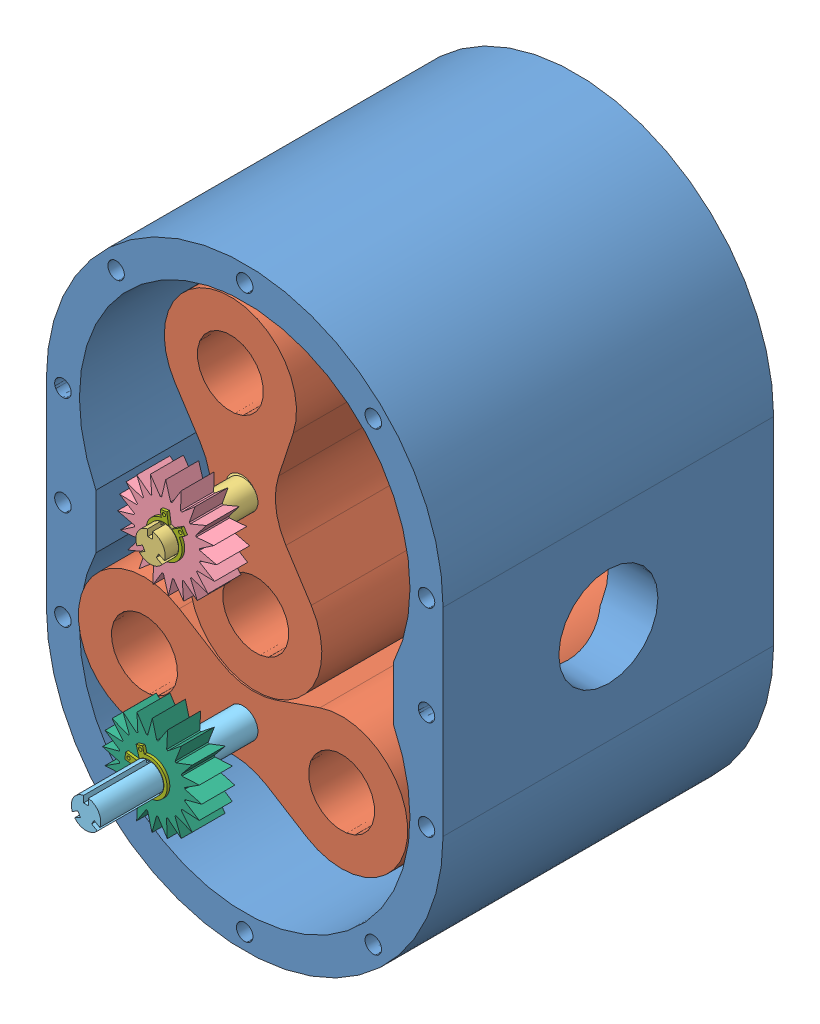
SolidWorks assembly 01-21-A-000-R00 Lobe Compressor Assembly, configuration Default. Lengths in mm.
Overall size (120 180 148).
9 component instances, 7 part files, 20 mates.
Components (placement in the parent):
- 01-21-P-001-R00 Compressor Housing-1: 01-21-P-001-R00 Compressor Housing [Default] at origin size (120 180 100)
- 01-21-P-002-R00 Compressor Top Lobe-1: 01-21-P-002-R00 Compressor Top Lobe [Default] at (0 30 5.5) x (0.991825 0.127605 0) z (0 0 1) size (40 100 90)
- 01-21-P-002-R00 Compressor Top Lobe-2: 01-21-P-002-R00 Compressor Top Lobe [Default] at (0 -30 5.5) x (-0.110138 -0.993916 0) z (0 0 1) size (40 100 90)
- 01-21-P-004-R00 Driven Lobe Shaft-1: 01-21-P-004-R00 Driven Lobe Shaft [Default] at (0 30 -46.5) x (0.999532 0.030602 0) z (0 0 1) size (10.29 11.89 125)
- 01-21-P-005-R00 Driven Lobe Shaft Gear-1: 01-21-P-005-R00 Driven Lobe Shaft Gear [Default] at (0 30 63.5) x (0.99962 0.027579 0) z (0 0 1) size (30 30 10)
- 01-21-P-006-R00 Drive Lobe Shaft-1: 01-21-P-006-R00 Drive Lobe Shaft [Default] at (0 -30 -47) x (0.999995 -0.003242 0) z (0 0 1) size (10.29 11.89 145)
- 01-21-P-007-R00 Drive Lobe Shaft Gear-1: 01-21-P-007-R00 Drive Lobe Shaft Gear [Default] at (0 -30 68) x (0.999995 -0.003242 0) z (0 0 1) size (30 30 10)
- 01-21-P-008-Lobe Shaft Retaining Ring-3: 01-21-P-008-Lobe Shaft Retaining Ring [Default] at (0 -30 78.1) x (0.657768 0.75322 0) z (0 0 1) size (10.9 12.78 0.8)
- 01-21-P-008-Lobe Shaft Retaining Ring-4: 01-21-P-008-Lobe Shaft Retaining Ring [Default] at (0 30 73.6) x (0.910939 -0.412541 0) z (0 0 1) size (10.9 12.78 0.8)
Mates (geometry in assembly coordinates):
- Coincident1: coincident aligned: plane of 01-21-P-001-R00 Compressor Housing-1 through (0 0 0) normal (0 1 0); plane of assembly through (0 0 0) normal (0 1 0)
- Coincident2: coincident aligned: plane of 01-21-P-001-R00 Compressor Housing-1 through (0 0 0) normal (0 0 1); plane of assembly through (0 0 0) normal (0 0 1)
- Coincident3: coincident aligned: plane of 01-21-P-001-R00 Compressor Housing-1 through (0 0 0) normal (1 0 0); plane of assembly through (0 0 0) normal (1 0 0)
- Concentric1: concentric aligned: circle of 01-21-P-001-R00 Compressor Housing-1; circle of 01-21-P-002-R00 Compressor Top Lobe-1
- Distance1: distance = 0.5 mm anti-aligned: plane of 01-21-P-002-R00 Compressor Top Lobe-1 through (-3.8282 59.7548 -39.5) normal (0 0 -1); plane of 01-21-P-001-R00 Compressor Housing-1 through (0 30 -40) normal (0 0 1)
- Concentric2: concentric aligned: circle of 01-21-P-001-R00 Compressor Housing-1; circle of 01-21-P-002-R00 Compressor Top Lobe-2
- Distance2: distance = 0.5 mm anti-aligned: plane of 01-21-P-002-R00 Compressor Top Lobe-2 through (29.8175 -33.3041 -39.5) normal (0 0 -1); plane of 01-21-P-001-R00 Compressor Housing-1 through (0 30 -40) normal (0 0 1)
- Concentric3: concentric aligned: circle of 01-21-P-002-R00 Compressor Top Lobe-1; circle of 01-21-P-004-R00 Driven Lobe Shaft-1
- Distance4: distance = 0.5 mm anti-aligned: plane of 01-21-P-004-R00 Driven Lobe Shaft-1 through (0 30 -46.5) normal (0 0 -1); plane of 01-21-P-001-R00 Compressor Housing-1 through (0 30 -47) normal (0 0 1)
- Concentric4: concentric aligned: circle of 01-21-P-004-R00 Driven Lobe Shaft-1; circle of 01-21-P-005-R00 Driven Lobe Shaft Gear-1
- Coincident6: coincident anti-aligned: plane of 01-21-P-004-R00 Driven Lobe Shaft-1 through (0 30 63.5) normal (0 0 1); plane of 01-21-P-005-R00 Driven Lobe Shaft Gear-1 through (0 30 63.5) normal (0 0 -1)
- Concentric5: concentric aligned: circle of 01-21-P-002-R00 Compressor Top Lobe-2; circle of 01-21-P-006-R00 Drive Lobe Shaft-1
- Coincident7: coincident anti-aligned: plane of 01-21-P-001-R00 Compressor Housing-1 through (0 -30 -47) normal (0 0 1); plane of 01-21-P-006-R00 Drive Lobe Shaft-1 through (0 -30 -47) normal (0 0 -1)
- Width1: width anti-aligned: plane of 01-21-P-006-R00 Drive Lobe Shaft-1 through (0.7578 -27.5953 68) normal (-0.999995 0.003242 0); plane of 01-21-P-006-R00 Drive Lobe Shaft-1 through (-0.7422 -27.5904 68) normal (0.999995 -0.003242 0); plane of 01-21-P-007-R00 Drive Lobe Shaft Gear-1 through (0.45 -30.0015 78) normal (0.999995 -0.003242 0); plane of 01-21-P-007-R00 Drive Lobe Shaft Gear-1 through (-0.45 -29.9985 78) normal (-0.999995 0.003242 0)
- Concentric7: concentric aligned: circle of 01-21-P-006-R00 Drive Lobe Shaft-1; circle of 01-21-P-007-R00 Drive Lobe Shaft Gear-1
- Coincident8: coincident anti-aligned: plane of 01-21-P-006-R00 Drive Lobe Shaft-1 through (0 -30 68) normal (0 0 1); plane of 01-21-P-007-R00 Drive Lobe Shaft Gear-1 through (0 -30 68) normal (0 0 -1)
- Concentric11: concentric anti-aligned: circle of 01-21-P-006-R00 Drive Lobe Shaft-1; circle of 01-21-P-008-Lobe Shaft Retaining Ring-3
- Width4: width anti-aligned: plane of 01-21-P-006-R00 Drive Lobe Shaft-1 through (0.0145 -25.5295 78) normal (0 0 1); plane of 01-21-P-006-R00 Drive Lobe Shaft-1 through (0.0113 -26.5295 79) normal (0 0 -1); plane of 01-21-P-008-Lobe Shaft Retaining Ring-3 through (0 -30 78.1) normal (0 0 -1); plane of 01-21-P-008-Lobe Shaft Retaining Ring-3 through (0 -30 78.9) normal (0 0 1)
- Concentric12: concentric anti-aligned: circle of 01-21-P-004-R00 Driven Lobe Shaft-1; circle of 01-21-P-008-Lobe Shaft Retaining Ring-4
- Width5: width anti-aligned: plane of 01-21-P-004-R00 Driven Lobe Shaft-1 through (-0.1368 34.4684 73.5) normal (0 0 1); plane of 01-21-P-004-R00 Driven Lobe Shaft-1 through (-0.1062 33.4689 74.5) normal (0 0 -1); plane of 01-21-P-008-Lobe Shaft Retaining Ring-4 through (0 30 73.6) normal (0 0 -1); plane of 01-21-P-008-Lobe Shaft Retaining Ring-4 through (0 30 74.4) normal (0 0 1)
